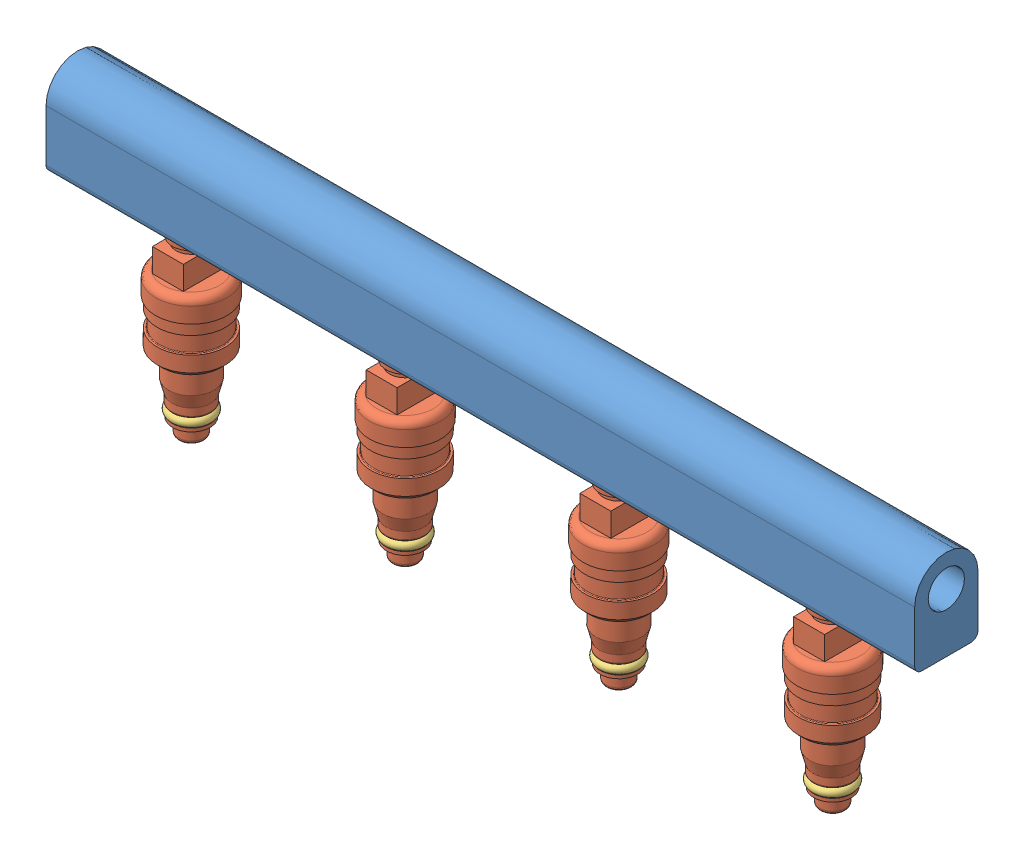
SolidWorks assembly Fuel_Rail_with_Injectors, configuration Default. Lengths in mm.
Overall size (304.8 96.72 32.6).
17 component instances, 3 part files, 12 mates.
Components (placement in the parent):
- Fuel_rail-1: Fuel_rail [Default] at (-13.4447 34.95 -13.4143) size (304.8 31.75 22.23)
- 2010_injectors-1: 2010_injectors [Default] at (-123.033 -28.5199 -29.993) size (24.92 77.22 32.6)
  - 2010_injectors-1: 2010_injectors [Default] at (-2.9117 -22.1408 16.5786) size (24.92 77.22 32.6)
  - Injector_o-ring-1: Injector_o-ring [AS568 - 011] at (-2.9117 51.1382 16.5786) x (-0.537903 0 -0.843006) z (-0.843006 0 0.537903) size (14.48 3.3 14.48)
  - Injector_o-ring-2: Injector_o-ring [AS568 - 011] at (-2.9117 -14.0636 16.5786) x (0.996935 0 0.078229) z (-0.078229 0 0.996935) size (14.48 3.3 14.48)
- 2010_injectors-2: 2010_injectors [Default] at (-48.033 -28.5199 -29.993) size (24.92 77.22 32.6)
  - 2010_injectors-1: 2010_injectors [Default] at (-2.9117 -22.1408 16.5786) size (24.92 77.22 32.6)
  - Injector_o-ring-1: Injector_o-ring [AS568 - 011] at (-2.9117 51.1382 16.5786) x (-0.537903 0 -0.843006) z (-0.843006 0 0.537903) size (14.48 3.3 14.48)
  - Injector_o-ring-2: Injector_o-ring [AS568 - 011] at (-2.9117 -14.0636 16.5786) x (0.996935 0 0.078229) z (-0.078229 0 0.996935) size (14.48 3.3 14.48)
- 2010_injectors-3: 2010_injectors [Default] at (26.967 -28.5199 -29.993) size (24.92 77.22 32.6)
  - 2010_injectors-1: 2010_injectors [Default] at (-2.9117 -22.1408 16.5786) size (24.92 77.22 32.6)
  - Injector_o-ring-1: Injector_o-ring [AS568 - 011] at (-2.9117 51.1382 16.5786) x (-0.537903 0 -0.843006) z (-0.843006 0 0.537903) size (14.48 3.3 14.48)
  - Injector_o-ring-2: Injector_o-ring [AS568 - 011] at (-2.9117 -14.0636 16.5786) x (0.996935 0 0.078229) z (-0.078229 0 0.996935) size (14.48 3.3 14.48)
- 2010_injectors-4: 2010_injectors [Default] at (101.967 -28.5199 -29.993) size (24.92 77.22 32.6)
  - 2010_injectors-1: 2010_injectors [Default] at (-2.9117 -22.1408 16.5786) size (24.92 77.22 32.6)
  - Injector_o-ring-1: Injector_o-ring [AS568 - 011] at (-2.9117 51.1382 16.5786) x (-0.537903 0 -0.843006) z (-0.843006 0 0.537903) size (14.48 3.3 14.48)
  - Injector_o-ring-2: Injector_o-ring [AS568 - 011] at (-2.9117 -14.0636 16.5786) x (0.996935 0 0.078229) z (-0.078229 0 0.996935) size (14.48 3.3 14.48)
Mates (geometry in assembly coordinates):
- Concentric1: concentric aligned: cylinder of Fuel_rail-1 through (99.0553 14.3125 -13.4143) axis (0 -1 0) radius 6.5; cylinder of ? through (99.0553 -50.6607 -13.4143) axis (0 -1 0) radius 6.6421
- Concentric2: concentric aligned: cylinder of Fuel_rail-1 through (24.0553 14.3125 -13.4143) axis (0 -1 0) radius 6.5; cylinder of ? through (24.0553 -50.6607 -13.4143) axis (0 -1 0) radius 6.6421
- Concentric3: concentric aligned: cylinder of Fuel_rail-1 through (-50.9447 14.3125 -13.4143) axis (0 -1 0) radius 6.5; cylinder of ? through (-50.9447 -50.6607 -13.4143) axis (0 -1 0) radius 6.6421
- Concentric4: concentric aligned: cylinder of Fuel_rail-1 through (-125.9447 14.3125 -13.4143) axis (0 -1 0) radius 6.5; cylinder of ? through (-125.9447 -50.6607 -13.4143) axis (0 -1 0) radius 6.6421
- Coincident1: coincident aligned: plane of ? through (99.0553 -50.6607 -13.4143) normal (0 -1 0); plane of ? through (24.0553 -50.6607 -13.4143) normal (0 -1 0)
- Coincident2: coincident aligned: plane of ? through (-50.9447 -50.6607 -13.4143) normal (0 -1 0); plane of ? through (24.0553 -50.6607 -13.4143) normal (0 -1 0)
- Coincident3: coincident aligned: plane of ? through (-125.9447 -50.6607 -13.4143) normal (0 -1 0); plane of ? through (-50.9447 -50.6607 -13.4143) normal (0 -1 0)
- Distance1: distance = 6.35 mm anti-aligned: plane of Fuel_rail-1 through (-165.8447 14.3125 -4.8418) normal (0 -1 0); plane of 2010_injectors-4/2010_injectors-1 through (93.6324 7.9625 -19.6373) normal (0 1 0)
- Parallel1: parallel aligned: plane of ? through (18.5141 7.9625 -47.0678) normal (0.915755 0 -0.401738); plane of ? through (93.5141 7.9625 -47.0678) normal (0.915755 0 -0.401738)
- Parallel2: parallel aligned: plane of 2010_injectors-2/2010_injectors-1 through (-42.4992 7.9625 -46.4588) normal (1 0 0); plane of 2010_injectors-3/2010_injectors-1 through (32.5008 7.9625 -46.4588) normal (1 0 0)
- Parallel3: parallel aligned: plane of 2010_injectors-1/2010_injectors-1 through (-117.4992 7.9625 -46.4588) normal (1 0 0); plane of 2010_injectors-2/2010_injectors-1 through (-42.4992 7.9625 -46.4588) normal (1 0 0)
- Parallel4: parallel aligned: plane of Fuel_rail-1 through (138.9553 34.95 -13.4143) normal (1 0 0); plane of 2010_injectors-4/2010_injectors-1 through (107.5008 7.9625 -46.4588) normal (1 0 0)
